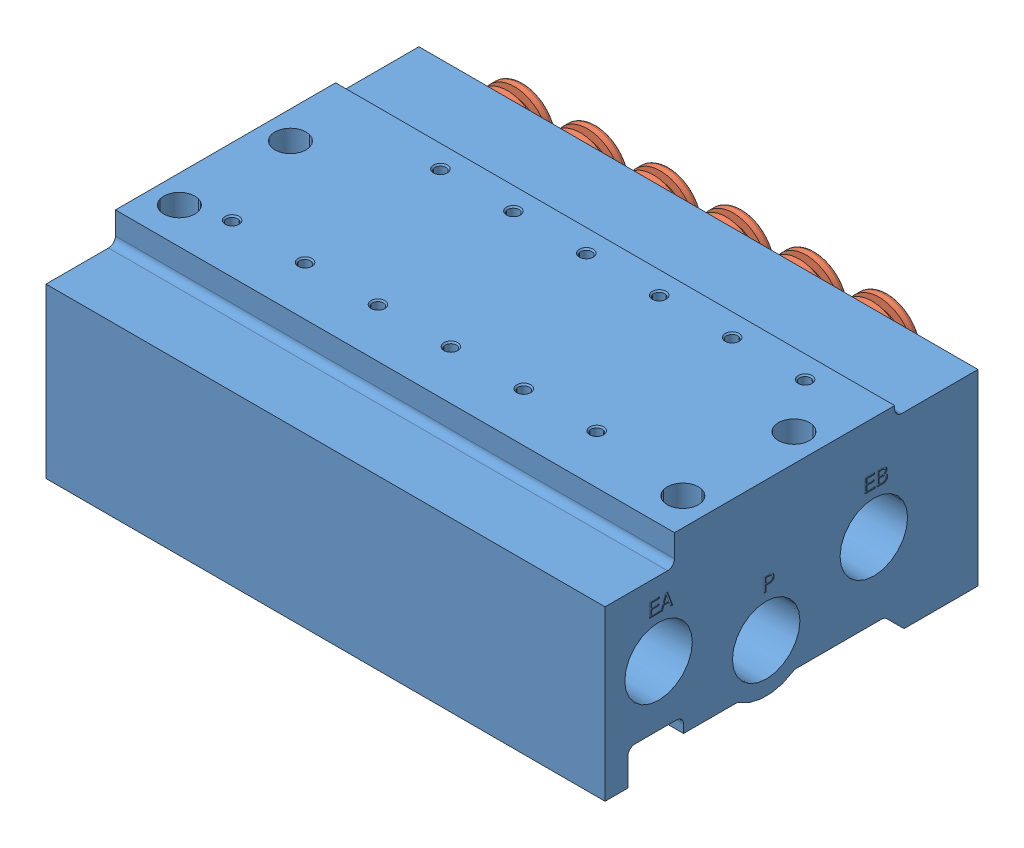
SolidWorks assembly 6 Station Manifold 217-2954, configuration Default. Lengths in mm.
Overall size (80.5 28.5 58.2).
13 component instances, 2 part files, 0 mates.
Components (placement in the parent):
- Copy of 217-2954-001 Rev1_41^6 Station Manifold 217-2954-1: Copy of 217-2954-001 Rev1_41^6 Station Manifold 217-2954 [Default] at origin size (80.5 28.5 53.7) (virtual)
- Copy of 217-2954-002 Rev1_1000-50A-N7^6 Station Manifold 217-2954-1: Copy of 217-2954-002 Rev1_1000-50A-N7^6 Station Manifold 217-2954 [Default] at (-10.5 -22 -15.65) x (1 0 0) z (0 0 -1) size (10 10 15.7) (virtual)
- Copy of 217-2954-002 Rev1_1000-50A-N7^6 Station Manifold 217-2954-2: Copy of 217-2954-002 Rev1_1000-50A-N7^6 Station Manifold 217-2954 [Default] at (-17.5 -7.8 -15.65) x (1 0 0) z (0 0 -1) size (10 10 15.7) (virtual)
- Copy of 217-2954-002 Rev1_1000-50A-N7^6 Station Manifold 217-2954-3: Copy of 217-2954-002 Rev1_1000-50A-N7^6 Station Manifold 217-2954 [Default] at (-21 -22 -15.65) x (1 0 0) z (0 0 -1) size (10 10 15.7) (virtual)
- Copy of 217-2954-002 Rev1_1000-50A-N7^6 Station Manifold 217-2954-4: Copy of 217-2954-002 Rev1_1000-50A-N7^6 Station Manifold 217-2954 [Default] at (-28 -7.8 -15.65) x (1 0 0) z (0 0 -1) size (10 10 15.7) (virtual)
- Copy of 217-2954-002 Rev1_1000-50A-N7^6 Station Manifold 217-2954-5: Copy of 217-2954-002 Rev1_1000-50A-N7^6 Station Manifold 217-2954 [Default] at (-31.5 -22 -15.65) x (1 0 0) z (0 0 -1) size (10 10 15.7) (virtual)
- Copy of 217-2954-002 Rev1_1000-50A-N7^6 Station Manifold 217-2954-6: Copy of 217-2954-002 Rev1_1000-50A-N7^6 Station Manifold 217-2954 [Default] at (-38.5 -7.8 -15.65) x (1 0 0) z (0 0 -1) size (10 10 15.7) (virtual)
- Copy of 217-2954-002 Rev1_1000-50A-N7^6 Station Manifold 217-2954-7: Copy of 217-2954-002 Rev1_1000-50A-N7^6 Station Manifold 217-2954 [Default] at (-42 -22 -15.65) x (1 0 0) z (0 0 -1) size (10 10 15.7) (virtual)
- Copy of 217-2954-002 Rev1_1000-50A-N7^6 Station Manifold 217-2954-8: Copy of 217-2954-002 Rev1_1000-50A-N7^6 Station Manifold 217-2954 [Default] at (-52.5 -22 -15.65) x (1 0 0) z (0 0 -1) size (10 10 15.7) (virtual)
- Copy of 217-2954-002 Rev1_1000-50A-N7^6 Station Manifold 217-2954-9: Copy of 217-2954-002 Rev1_1000-50A-N7^6 Station Manifold 217-2954 [Default] at (-63 -22 -15.65) x (1 0 0) z (0 0 -1) size (10 10 15.7) (virtual)
- Copy of 217-2954-002 Rev1_1000-50A-N7^6 Station Manifold 217-2954-10: Copy of 217-2954-002 Rev1_1000-50A-N7^6 Station Manifold 217-2954 [Default] at (-49 -7.8 -15.65) x (1 0 0) z (0 0 -1) size (10 10 15.7) (virtual)
- Copy of 217-2954-002 Rev1_1000-50A-N7^6 Station Manifold 217-2954-11: Copy of 217-2954-002 Rev1_1000-50A-N7^6 Station Manifold 217-2954 [Default] at (-59.5 -7.8 -15.65) x (1 0 0) z (0 0 -1) size (10 10 15.7) (virtual)
- Copy of 217-2954-002 Rev1_1000-50A-N7^6 Station Manifold 217-2954-12: Copy of 217-2954-002 Rev1_1000-50A-N7^6 Station Manifold 217-2954 [Default] at (-70 -7.8 -15.65) x (1 0 0) z (0 0 -1) size (10 10 15.7) (virtual)
